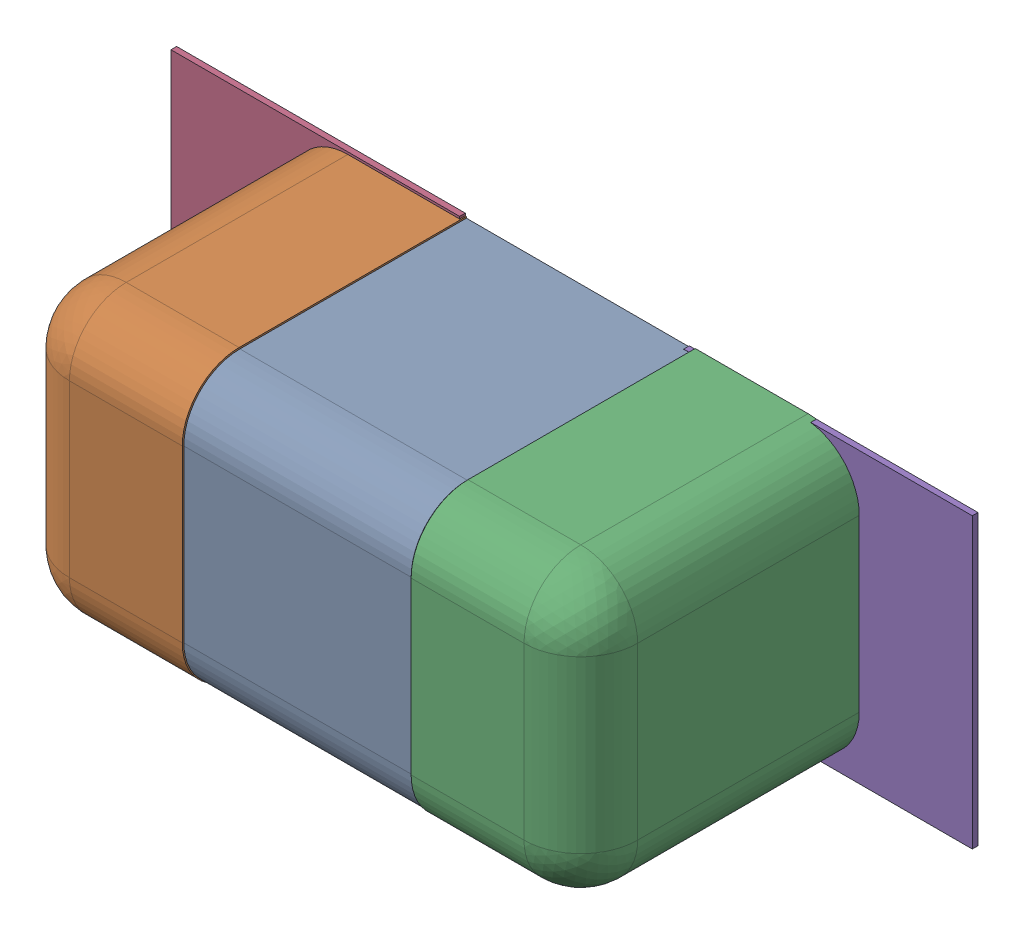
SolidWorks assembly C139, configuration Défaut. Lengths in mm.
Overall size (1.41 0.51 0.5).
8 component instances, 4 part files, 0 mates.
Components (placement in the parent):
- 6324936752-1: 6324936752 [Défaut] at (15.806 -23.0632 0) x (1 0 0) z (0 -1 0) size (1 0.5 0.5)
  - Open CASCADE STEP translator 7.5 2.114.1.1-1: Open CASCADE STEP translator 7.5 2.114.1.1 [Défaut] at origin size (0.4 0.5 0.5)
  - Open CASCADE STEP translator 7.5 2.114.1.2-1: Open CASCADE STEP translator 7.5 2.114.1.2 [Défaut] at origin size (0.3 0.5 0.5)
  - Open CASCADE STEP translator 7.5 2.114.1.3-1: Open CASCADE STEP translator 7.5 2.114.1.3 [Défaut] at origin size (0.3 0.5 0.5)
- 6504207776-1: 6504207776 [Défaut] at (15.3487 -23.0632 0) size (0.51 0.51 0.01)
  - Extruded-1: Extruded [Défaut] at origin size (0.51 0.51 0.01)
- 6504207776-2: 6504207776 [Défaut] at (16.251 -23.0684 0) size (0.51 0.51 0.01)
  - Extruded-1: Extruded [Défaut] at origin size (0.51 0.51 0.01)
